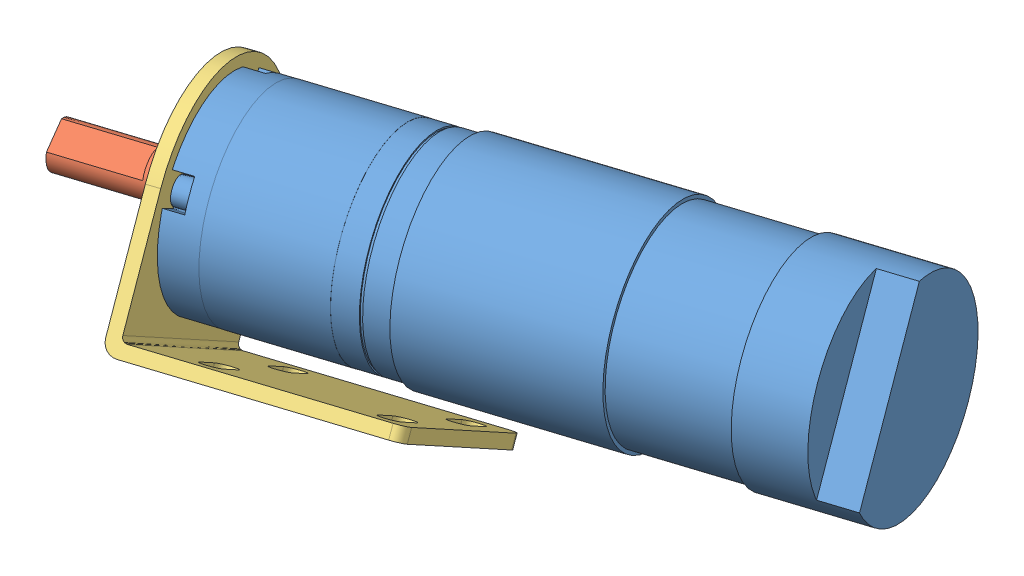
SolidWorks assembly DC-Planet-Geared-motor, configuration Default. Lengths in mm.
Overall size (136.62 59.6 85.87).
4 component instances, 3 part files, 4 mates.
Components (placement in the parent):
- DC planet geared motor-1: DC planet geared motor [Default] at (10.5325 5.398 30.6003) size (136.62 52.79 81.46)
  - motor-1: motor [Default] at (-31.8628 68.735 102.3609) x (0.168703 -0.836716 0.521005) z (0.239325 0.547535 0.801829) size (37.3 109.75 37.3)
  - shaft-1: shaft [Default] at (-25.6477 68.8038 100.4589) x (-0.253239 0.531568 -0.808273) z (0.146993 0.84695 0.510949) size (8 31.3 8)
- gá đỡ động cơ-2: gá đỡ động cơ [Default] at (-21.3303 74.1329 132.9612) x (-0.168703 0.836716 -0.521005) z (-0.956171 -0.010582 0.292618) size (44.4 40.1 46.8)
Mates (geometry in assembly coordinates):
- InPlace1: in place: plane of DC planet geared motor-1/motor-1 through (-21.3303 74.1329 132.9612) normal (-0.956171 -0.010582 0.292618); plane of ? through (-55.953 -0.6192 17.1234) normal (-0.956171 -0.010582 0.292618); moOrthogonalPlaneRef_w of DC planet geared motor-1/motor-1 through (-21.3303 74.1329 132.9612) normal (-0.956171 -0.010582 0.292618); plane of ? through (-55.953 -0.6192 17.1234) normal (-0.011066 0.999939 0); plane of DC planet geared motor-1/motor-1 through (-21.3303 74.1329 132.9612) normal (-0.956171 -0.010582 0.292618); plane of ? through (-55.953 -0.6192 17.1234) normal (0.2926 0.003238 0.95623); plane of DC planet geared motor-1/motor-1 through (-21.3303 74.1329 132.9612) normal (-0.956171 -0.010582 0.292618); unknown of gá đỡ động cơ-2
- Coincident1: coincident aligned: plane of DC planet geared motor-1/motor-1; plane of gá đỡ động cơ-2
- Coincident2: coincident aligned: moOrthogonalPlaneRef_w of DC planet geared motor-1/motor-1 through (-21.3303 74.1329 132.9612) normal (-0.239325 -0.547535 -0.801829); plane of gá đỡ động cơ-2 through (-21.3303 74.1329 132.9612) normal (-0.239325 -0.547535 -0.801829)
- Coincident3: coincident anti-aligned: moOrthogonalPlaneRef_w of DC planet geared motor-1/motor-1 through (-21.3303 74.1329 132.9612) normal (0.168703 -0.836716 0.521005); plane of gá đỡ động cơ-2 through (-21.3303 74.1329 132.9612) normal (-0.168703 0.836716 -0.521005)
